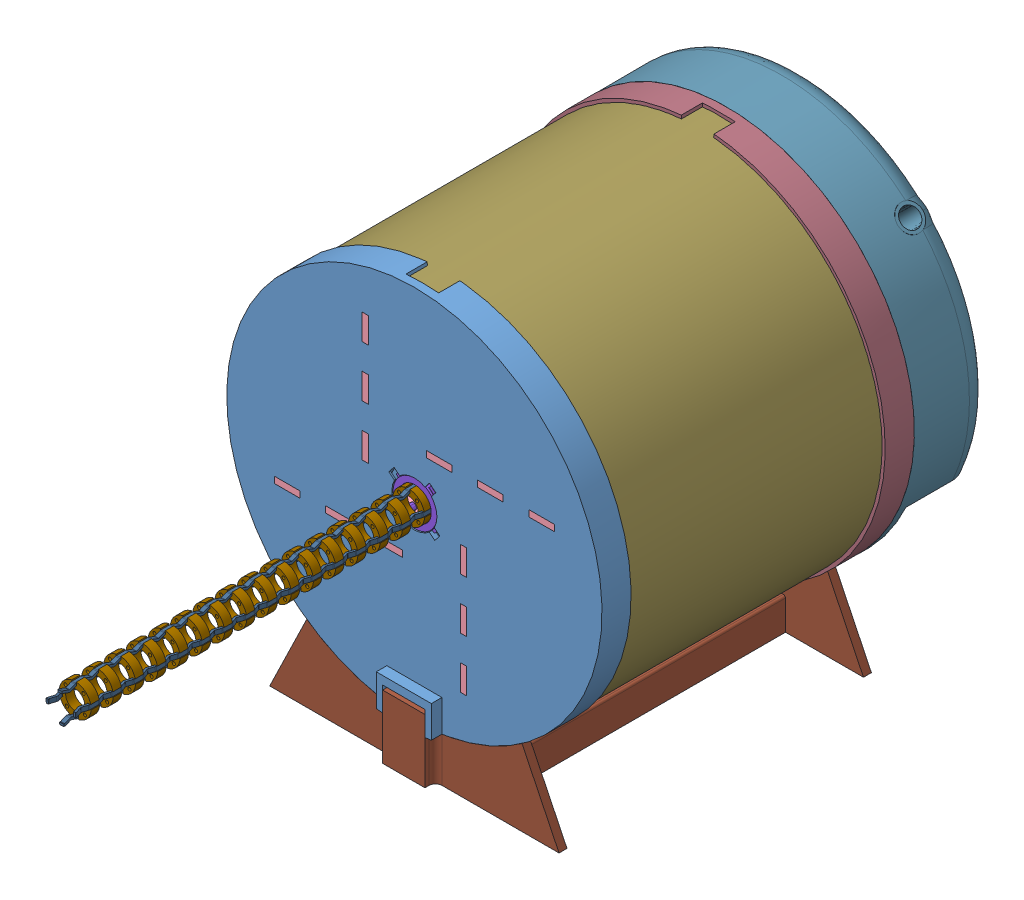
SolidWorks assembly ContinuumRobot, configuration Default. Lengths in mm.
Overall size (199.74 208.48 363.93).
87 component instances, 16 part files, 24 mates.
Components (placement in the parent):
- FrontCover-1: FrontCover [Default] at (-7.5052 108.611 -0.1815) x (0 -1 0) z (0 0 1) size (177.22 177.22 18.75)
- ServoSet-1: ServoSet [Default] at (-166.7141 140.7245 173.5818) x (0 1 0) z (0 0 -1) size (82.84 52.3 148.09)
  - 55gServoAndAttachment-1: 55gServoAndAttachment [Default] at (-42.4416 98.8668 240.9659) x (0 0 -1) z (1 0 0) size (24.11 48.3 54.1)
    - 55gServoMotor-1: 55gServoMotor [Default] at (29.3026 10.0421 49.0781) size (20.3 45.5 54.1)
    - CircularAttachment-1: CircularAttachment [Default] at (29.3026 56.1421 60.3281) x (0.973354 0 0.229307) z (-0.229307 0 0.973354) size (20.05 5.6 20.05)
  - ServoHolderDirect-2: ServoHolderDirect [Default] at (3.7865 137.5089 247.5133) x (-1 0 0) z (0 0 1) size (72.5 3 147.5)
  - 55gServoAndAttachment-4: 55gServoAndAttachment [Default] at (64.7146 98.8668 238.0606) x (0 0 1) z (-1 0 0) size (24.11 48.3 54.1)
    - 55gServoMotor-1: 55gServoMotor [Default] at (29.3026 10.0421 49.0781) size (20.3 45.5 54.1)
    - CircularAttachment-1: CircularAttachment [Default] at (29.3026 56.1421 60.3281) x (0.973354 0 0.229307) z (-0.229307 0 0.973354) size (20.05 5.6 20.05)
  - 55gServoAndAttachment-5: 55gServoAndAttachment [Default] at (53.0146 98.8668 274.0606) x (0 0 1) z (-1 0 0) size (24.11 48.3 54.1)
    - 55gServoMotor-1: 55gServoMotor [Default] at (29.3026 10.0421 49.0781) size (20.3 45.5 54.1)
    - CircularAttachment-1: CircularAttachment [Default] at (29.3026 56.1421 60.3281) x (0.973354 0 0.229307) z (-0.229307 0 0.973354) size (20.05 5.6 20.05)
  - MotorTransmissionMedium-1: MotorTransmissionMedium [Default] at (4.3865 154.2089 267.3633) x (0.973354 0 0.229307) z (0.229307 0 -0.973354) size (44 4 44)
  - MotorTransmissionSmall-1: MotorTransmissionSmall [Default] at (-7.3135 154.2089 303.3633) x (0.973354 0 0.229307) z (0.229307 0 -0.973354) size (24 4 24)
  - MotorTransmissionLarge-1: MotorTransmissionLarge [Default] at (17.8865 154.2089 211.6633) x (-0.973354 0 -0.229307) z (-0.229307 0 0.973354) size (64 4 64)
- ServoSet-3: ServoSet [Default] at (-39.6187 -50.5979 173.5818) x (-1 0 0) z (0 0 -1) size (82.84 52.3 148.09)
  - 55gServoAndAttachment-1: 55gServoAndAttachment [Default] at (-42.4416 98.8668 240.9659) x (0 0 -1) z (1 0 0) size (24.11 48.3 54.1)
    - 55gServoMotor-1: 55gServoMotor [Default] at (29.3026 10.0421 49.0781) size (20.3 45.5 54.1)
    - CircularAttachment-1: CircularAttachment [Default] at (29.3026 56.1421 60.3281) x (0.973354 0 0.229307) z (-0.229307 0 0.973354) size (20.05 5.6 20.05)
  - ServoHolderDirect-2: ServoHolderDirect [Default] at (3.7865 137.5089 247.5133) x (-1 0 0) z (0 0 1) size (72.5 3 147.5)
  - 55gServoAndAttachment-4: 55gServoAndAttachment [Default] at (64.7146 98.8668 238.0606) x (0 0 1) z (-1 0 0) size (24.11 48.3 54.1)
    - 55gServoMotor-1: 55gServoMotor [Default] at (29.3026 10.0421 49.0781) size (20.3 45.5 54.1)
    - CircularAttachment-1: CircularAttachment [Default] at (29.3026 56.1421 60.3281) x (0.973354 0 0.229307) z (-0.229307 0 0.973354) size (20.05 5.6 20.05)
  - 55gServoAndAttachment-5: 55gServoAndAttachment [Default] at (53.0146 98.8668 274.0606) x (0 0 1) z (-1 0 0) size (24.11 48.3 54.1)
    - 55gServoMotor-1: 55gServoMotor [Default] at (29.3026 10.0421 49.0781) size (20.3 45.5 54.1)
    - CircularAttachment-1: CircularAttachment [Default] at (29.3026 56.1421 60.3281) x (0.973354 0 0.229307) z (-0.229307 0 0.973354) size (20.05 5.6 20.05)
  - MotorTransmissionMedium-1: MotorTransmissionMedium [Default] at (4.3865 154.2089 267.3633) x (0.973354 0 0.229307) z (0.229307 0 -0.973354) size (44 4 44)
  - MotorTransmissionSmall-1: MotorTransmissionSmall [Default] at (-7.3135 154.2089 303.3633) x (0.973354 0 0.229307) z (0.229307 0 -0.973354) size (24 4 24)
  - MotorTransmissionLarge-1: MotorTransmissionLarge [Default] at (17.8865 154.2089 211.6633) x (-0.973354 0 -0.229307) z (-0.229307 0 0.973354) size (64 4 64)
- ServoSet-4: ServoSet [Default] at (151.7037 76.4975 173.5818) x (0 -1 0) z (0 0 -1) size (82.84 52.3 148.09)
  - 55gServoAndAttachment-1: 55gServoAndAttachment [Default] at (-42.4416 98.8668 240.9659) x (0 0 -1) z (1 0 0) size (24.11 48.3 54.1)
    - 55gServoMotor-1: 55gServoMotor [Default] at (29.3026 10.0421 49.0781) size (20.3 45.5 54.1)
    - CircularAttachment-1: CircularAttachment [Default] at (29.3026 56.1421 60.3281) x (0.973354 0 0.229307) z (-0.229307 0 0.973354) size (20.05 5.6 20.05)
  - ServoHolderDirect-2: ServoHolderDirect [Default] at (3.7865 137.5089 247.5133) x (-1 0 0) z (0 0 1) size (72.5 3 147.5)
  - 55gServoAndAttachment-4: 55gServoAndAttachment [Default] at (64.7146 98.8668 238.0606) x (0 0 1) z (-1 0 0) size (24.11 48.3 54.1)
    - 55gServoMotor-1: 55gServoMotor [Default] at (29.3026 10.0421 49.0781) size (20.3 45.5 54.1)
    - CircularAttachment-1: CircularAttachment [Default] at (29.3026 56.1421 60.3281) x (0.973354 0 0.229307) z (-0.229307 0 0.973354) size (20.05 5.6 20.05)
  - 55gServoAndAttachment-5: 55gServoAndAttachment [Default] at (53.0146 98.8668 274.0606) x (0 0 1) z (-1 0 0) size (24.11 48.3 54.1)
    - 55gServoMotor-1: 55gServoMotor [Default] at (29.3026 10.0421 49.0781) size (20.3 45.5 54.1)
    - CircularAttachment-1: CircularAttachment [Default] at (29.3026 56.1421 60.3281) x (0.973354 0 0.229307) z (-0.229307 0 0.973354) size (20.05 5.6 20.05)
  - MotorTransmissionMedium-1: MotorTransmissionMedium [Default] at (4.3865 154.2089 267.3633) x (0.973354 0 0.229307) z (0.229307 0 -0.973354) size (44 4 44)
  - MotorTransmissionSmall-1: MotorTransmissionSmall [Default] at (-7.3135 154.2089 303.3633) x (0.973354 0 0.229307) z (0.229307 0 -0.973354) size (24 4 24)
  - MotorTransmissionLarge-1: MotorTransmissionLarge [Default] at (17.8865 154.2089 211.6633) x (-0.973354 0 -0.229307) z (-0.229307 0 0.973354) size (64 4 64)
- ServoSet-5: ServoSet [Default] at (24.6083 267.8199 173.5818) x (1 0 0) z (0 0 -1) size (82.84 52.3 148.09)
  - 55gServoAndAttachment-1: 55gServoAndAttachment [Default] at (-42.4416 98.8668 240.9659) x (0 0 -1) z (1 0 0) size (24.11 48.3 54.1)
    - 55gServoMotor-1: 55gServoMotor [Default] at (29.3026 10.0421 49.0781) size (20.3 45.5 54.1)
    - CircularAttachment-1: CircularAttachment [Default] at (29.3026 56.1421 60.3281) x (0.973354 0 0.229307) z (-0.229307 0 0.973354) size (20.05 5.6 20.05)
  - ServoHolderDirect-2: ServoHolderDirect [Default] at (3.7865 137.5089 247.5133) x (-1 0 0) z (0 0 1) size (72.5 3 147.5)
  - 55gServoAndAttachment-4: 55gServoAndAttachment [Default] at (64.7146 98.8668 238.0606) x (0 0 1) z (-1 0 0) size (24.11 48.3 54.1)
    - 55gServoMotor-1: 55gServoMotor [Default] at (29.3026 10.0421 49.0781) size (20.3 45.5 54.1)
    - CircularAttachment-1: CircularAttachment [Default] at (29.3026 56.1421 60.3281) x (0.973354 0 0.229307) z (-0.229307 0 0.973354) size (20.05 5.6 20.05)
  - 55gServoAndAttachment-5: 55gServoAndAttachment [Default] at (53.0146 98.8668 274.0606) x (0 0 1) z (-1 0 0) size (24.11 48.3 54.1)
    - 55gServoMotor-1: 55gServoMotor [Default] at (29.3026 10.0421 49.0781) size (20.3 45.5 54.1)
    - CircularAttachment-1: CircularAttachment [Default] at (29.3026 56.1421 60.3281) x (0.973354 0 0.229307) z (-0.229307 0 0.973354) size (20.05 5.6 20.05)
  - MotorTransmissionMedium-1: MotorTransmissionMedium [Default] at (4.3865 154.2089 267.3633) x (0.973354 0 0.229307) z (0.229307 0 -0.973354) size (44 4 44)
  - MotorTransmissionSmall-1: MotorTransmissionSmall [Default] at (-7.3135 154.2089 303.3633) x (0.973354 0 0.229307) z (0.229307 0 -0.973354) size (24 4 24)
  - MotorTransmissionLarge-1: MotorTransmissionLarge [Default] at (17.8865 154.2089 211.6633) x (-0.973354 0 -0.229307) z (-0.229307 0 0.973354) size (64 4 64)
- SpineAndLock-1: SpineAndLock [Default] at (10.9429 114.3681 -26.9318) x (-0.760407 0.649447 0) z (0 0 1) size (23.7 23.7 170.25)
  - SpineTwistLock-1: SpineTwistLock [Default] at (10.2892 -83.6412 26.4253) size (23.7 23.7 3)
  - Spine3Segments-1: Spine3Segments [Default] at (4.5097 28.4554 36.373) x (-0.707107 -0.707107 0) z (0.707107 -0.707107 0) size (14.85 168.25 14.85)
    - RigidDisc-1: RigidDisc [Default] at (4.4669 6.9477 12.6403) size (14.85 4 14.85)
    - RigidDisc-2: RigidDisc [Default] at (4.4669 -3.5523 12.6403) size (14.85 4 14.85)
    - RigidDisc-3: RigidDisc [Default] at (4.4669 -14.0523 12.6403) size (14.85 4 14.85)
    - RigidDisc-4: RigidDisc [Default] at (4.4669 -24.5523 12.6403) size (14.85 4 14.85)
    - RigidDisc-5: RigidDisc [Default] at (4.4669 -35.0523 12.6403) size (14.85 4 14.85)
    - Ligament-9: Ligament [Default] at (10.9419 10.9477 11.5653) x (0 -1 0) z (-1 0 0) size (168.25 2 2.03)
    - RigidDisc-16: RigidDisc [Default] at (4.4669 -45.5523 12.6403) size (14.85 4 14.85)
    - RigidDisc-17: RigidDisc [Default] at (4.4669 -56.0523 12.6403) size (14.85 4 14.85)
    - RigidDisc-18: RigidDisc [Default] at (4.4669 -66.5523 12.6403) size (14.85 4 14.85)
    - RigidDisc-19: RigidDisc [Default] at (4.4669 -77.0523 12.6403) size (14.85 4 14.85)
    - RigidDisc-20: RigidDisc [Default] at (4.4669 -87.5523 12.6403) size (14.85 4 14.85)
    - RigidDisc-21: RigidDisc [Default] at (4.4669 -98.0523 12.6403) size (14.85 4 14.85)
    - RigidDisc-22: RigidDisc [Default] at (4.4669 -108.5523 12.6403) size (14.85 4 14.85)
    - RigidDisc-23: RigidDisc [Default] at (4.4669 -119.0523 12.6403) size (14.85 4 14.85)
    - RigidDisc-24: RigidDisc [Default] at (4.4669 -129.5523 12.6403) size (14.85 4 14.85)
    - RigidDisc-25: RigidDisc [Default] at (4.4669 -140.0523 12.6403) size (14.85 4 14.85)
    - RigidDisc-26: RigidDisc [Default] at (4.4669 -150.5523 12.6403) size (14.85 4 14.85)
    - Ligament-11: Ligament [Default] at (3.3919 10.9477 6.1653) x (0 -1 0) z (0 0 1) size (168.25 2 2.03)
    - Ligament-12: Ligament [Default] at (-2.0081 10.9477 13.7153) x (0 -1 0) z (1 0 0) size (168.25 2 2.03)
    - Ligament-13: Ligament [Default] at (5.5419 10.9477 19.1153) x (0 -1 0) z (0 0 -1) size (168.25 2 2.03)
- BaseHolder-1: BaseHolder [Default] at (-7.5052 108.611 -2.0565) x (0 1 0) z (0 0 -1) size (197.22 177.22 157.5)
- HubCover-1: HubCover [Default] at (-7.5052 108.611 -143.9315) x (0.987237 -0.15926 0) z (0 0 1) size (174.22 174.22 140)
- MountAndBack-1: MountAndBack [Default] at (-136.0523 168.0928 -258.9838) x (0 -1 0) z (0 0 1) size (177.22 177.22 63.25)
  - BackCover-1: BackCover [Default] at (59.4818 128.5471 115.0523) size (177.22 177.22 18.75)
  - URVMount-1: URVMount [Default] at (59.4818 128.5471 111.3023) x (0 -1 0) z (0 0 1) size (177.22 177.22 49.5)
  - ServoDriver-1: ServoDriver [Default] at (43.0849 82.2579 106.3023) x (0 0 1) z (-1 0 0) size (2 25 62.1)
  - arduinoUnor-1: arduinoUnor [Default] at (54.6997 184.2196 96.9884) x (0 1 0) z (0 0 -1) size (54 75 15)
Mates (geometry in assembly coordinates):
- Concentric1: concentric aligned: cylinder of FrontCover-1 through (-7.5052 108.611 -3.9315) axis (0 0 1) radius 10.65; cylinder of SpineAndLock-1/SpineTwistLock-1 through (-7.5052 108.611 -3.5065) axis (0 0 1) radius 10.35
- Concentric2: concentric anti-aligned: cylinder of FrontCover-1 through (-7.5052 108.611 -0.1815) axis (0 0 -1) radius 88.611; cylinder of BackHubDirect-1 through (0 106.546 -147.5) axis (0 0 1) radius 88.611
- Concentric13: concentric anti-aligned: cylinder of FrontCover-1 through (-7.5052 108.611 -0.1815) axis (0 0 -1) radius 88.611; cylinder of BaseHolder-1 through (-7.5052 108.611 -3.9315) axis (0 0 1) radius 88.611
- Coincident16: coincident aligned: plane of FrontHubDirect-1 through (-7.5052 108.611 -0.1815) normal (0 0 1); plane of BaseHolderDirect-1 through (-7.5052 108.611 -0.1815) normal (0 0 1)
- Parallel1: parallel aligned: plane of FrontCover-1 through (-7.5052 174.761 -10.1815) normal (0 -1 0); plane of BaseHolder-1 through (-75.8304 0 -3.9315) normal (0 -1 0)
- Tangent2: tangent anti-aligned: face of BackHubDirect-1; plane of BackHubDirect-1 through (56 136.046 -160.5) normal (0 0 -1)
- Coincident17: coincident anti-aligned: plane of BackHubDirect-1 through (0 106.546 -150.5) normal (0 0 -1); plane of ServoDriverDirect-1 through (-35.2892 152.4928 -150.5) normal (0 0 1)
- Concentric16: concentric anti-aligned: cylinder of BackHubDirect-1 through (0 106.546 -147.5) axis (0 0 1) radius 88.611; cylinder of HubCover-1 through (-7.5052 108.611 -3.9315) axis (0 0 -1) radius 87.111
- Coincident18: coincident anti-aligned: plane of FrontCover-1 through (-7.5052 108.611 -3.9315) normal (0 0 -1); circle of HubCover-1
- Coincident19: coincident anti-aligned: plane of FrontCover-1 through (-29.2052 114.261 -10.1815) normal (0 1 0); plane of ServoSet-1/ServoHolderDirect-2 through (-32.2052 114.261 -73.9315) normal (0 -1 0)
- Coincident20: coincident anti-aligned: plane of FrontCover-1 through (-29.2052 114.261 -10.1815) normal (-1 0 0); plane of ServoSet-1/ServoHolderDirect-2 through (-29.2052 144.511 -73.9315) normal (1 0 0)
- Coincident21: coincident aligned: plane of FrontHubDirect-1 through (-7.5052 108.611 -0.1815) normal (0 0 1); plane of ServoSet-1/ServoHolderDirect-2 through (-32.2052 144.511 -0.1815) normal (0 0 1)
- Coincident22: coincident aligned: plane of ServoSet-1/ServoHolderDirect-2 through (-32.2052 144.511 -147.6815) normal (0 0 -1); plane of BackHubDirect-1 through (0 106.546 -147.5) normal (0 0 -1)
- Coincident23: coincident anti-aligned: plane of ServoSet-1/ServoHolderDirect-2 through (-32.2052 144.511 -73.9315) normal (-1 0 0); plane of BackHubDirect-1 through (-24.7 106.546 -153.75) normal (1 0 0)
- Tangent7: tangent anti-aligned: cylinder of ? through (56 136.046 -160.5) axis (0 0 1) radius 1.5; edge_curve of ?
- Tangent8: tangent anti-aligned: cylinder of ? through (25 136.046 -160.5) axis (0 0 1) radius 1.5; edge_curve of ?
- Concentric17: concentric anti-aligned: cylinder of BackHubDirect-1 through (-36.3499 151.4322 -150.5) axis (0 0 1) radius 0.75; cylinder of ServoDriverDirect-1 through (-36.3499 151.4322 -150.5) axis (0 0 -1) radius 1
- Concentric18: concentric anti-aligned: cylinder of BackHubDirect-1 through (-56.2286 151.4322 -150.5) axis (0 0 1) radius 0.75; cylinder of ServoDriverDirect-1 through (-56.2286 151.4322 -150.5) axis (0 0 -1) radius 1
- Coincident24: coincident anti-aligned: plane of BaseHolder-1 through (-75.8304 0 -3.9315) normal (0 -1 0)
- Concentric19: concentric anti-aligned: cylinder of FrontCover-1 through (-7.5052 108.611 -0.1815) axis (0 0 -1) radius 88.611; cylinder of MountAndBack-1/BackCover-1 through (-7.5052 108.611 -147.6815) axis (0 0 1) radius 88.611
- Coincident27: coincident aligned: plane of FrontCover-1 through (0.2178 196.8848 -13.9315) normal (-0.996195 0.087156 0); plane of MountAndBack-1/BackCover-1 through (0.2178 196.8848 -133.9315) normal (-0.996195 0.087156 0)
- Coincident28: coincident aligned: plane of ServoSet-1/ServoHolderDirect-2 through (-32.2052 144.511 -147.6815) normal (0 0 -1); plane of MountAndBack-1/BackCover-1 through (-7.5052 108.611 -147.6815) normal (0 0 -1)
- Concentric20: concentric aligned: cylinder of FrontCover-1 through (-7.5052 108.611 -0.1815) axis (0 0 -1) radius 88.611; cylinder of HubCover-1 through (-7.5052 108.611 -3.9315) axis (0 0 -1) radius 87.111
- Coincident29: coincident anti-aligned: plane of FrontCover-1 through (-7.5052 108.611 -2.5065) normal (0 0 1); plane of SpineAndLock-1/SpineTwistLock-1 through (-0.674 114.4151 -2.5065) normal (0 0 -1)
